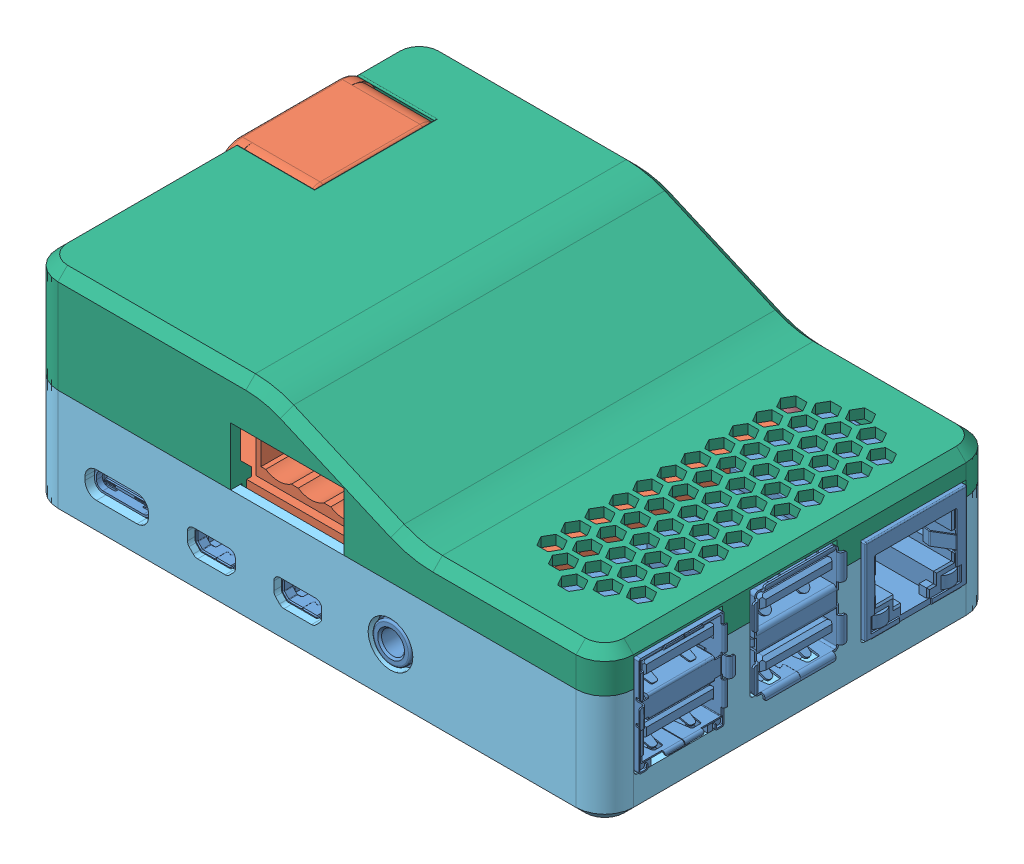
SolidWorks assembly AndroidAutoPi, configuration Default. Lengths in mm.
Overall size (91.49 34.28 61).
18 component instances, 7 part files, 35 mates.
Components (placement in the parent):
- Raspberry Pi 4 Model B-1: Raspberry Pi 4 Model B [Default] at (35.8475 44.9934 67.9064) size (88.99 19.9 58.4)
- PCB_AndroidAuto-1: PCB_AndroidAuto [Default] at (-6.6525 55.7834 95.9064) x (1 0 0) z (0 1 0) size (67.39 56 24.41)
- entretoiseM2.5x10_970100151-1: entretoiseM2.5x10_970100151 [Default] at (-3.1525 45.7834 92.4064) x (-0.708212 0 -0.705999) z (0.705999 0 -0.708212) size (6.35 10 5)
- entretoiseM2.5x10_970100151-2: entretoiseM2.5x10_970100151 [Default] at (54.8475 45.7834 92.4064) x (0.547024 0 -0.837117) z (0.837117 0 0.547024) size (6.35 10 5)
- entretoiseM2.5x10_970100151-3: entretoiseM2.5x10_970100151 [Default] at (-3.1525 45.7834 43.4064) size (6.35 10 5)
- entretoiseM2.5x10_970100151-4: entretoiseM2.5x10_970100151 [Default] at (54.8475 45.7834 43.4064) size (6.35 10 5)
- hexalobular socket pan head_iso-1: hexalobular socket pan head_iso [ISO 14583 - M2.5 x 3 x 2.1 - 4.8-N] at (54.8475 54.3834 43.4064) size (5 5.1 5)
- hexalobular socket pan head_iso-2: hexalobular socket pan head_iso [ISO 14583 - M2.5 x 3 x 2.1 - 4.8-N] at (54.8475 54.3834 92.4064) size (5 5.1 5)
- hexalobular socket pan head_iso-3: hexalobular socket pan head_iso [ISO 14583 - M2.5 x 3 x 2.1 - 4.8-N] at (-3.1525 54.3834 92.4064) size (5 5.1 5)
- hexalobular socket pan head_iso-4: hexalobular socket pan head_iso [ISO 14583 - M2.5 x 3 x 2.1 - 4.8-N] at (-3.1525 54.3834 43.4064) size (5 5.1 5)
- hexalobular socket pan head_iso-5: hexalobular socket pan head_iso [ISO 14583 - M2.5 x 6 x 5.1 - 4.8-N] at (54.8475 47.2034 43.4064) x (0.835617 0 0.549312) z (0.549312 0 -0.835617) size (5 8.1 5)
- hexalobular socket pan head_iso-6: hexalobular socket pan head_iso [ISO 14583 - M2.5 x 6 x 5.1 - 4.8-N] at (-3.1525 47.2034 43.4064) x (0.985596 0 0.169116) z (0.169116 0 -0.985596) size (5 8.1 5)
- hexalobular socket pan head_iso-7: hexalobular socket pan head_iso [ISO 14583 - M2.5 x 6 x 5.1 - 4.8-N] at (-3.1525 47.2034 92.4064) x (0.842129 0 0.539277) z (0.539277 0 -0.842129) size (5 8.1 5)
- hexalobular socket pan head_iso-8: hexalobular socket pan head_iso [ISO 14583 - M2.5 x 6 x 5.1 - 4.8-N] at (54.8475 47.2034 92.4064) x (0.76595 0 0.6429) z (0.6429 0 -0.76595) size (5 8.1 5)
- case_bottom-1: case_bottom [Défaut] at (35.8475 39.7034 67.9064) size (90 17.5 61)
- case_top-1: case_top [Défaut] at (35.8475 55.7034 67.9064) size (90 17.68 61)
- pxc_1757022_06_MSTB-2-5-3-ST-5-08_3D.stp-1: pxc_1757022_06_MSTB-2-5-3-ST-5-08_3D.stp [Défaut] at (23.6075 57.6575 104.8835) x (1 0 0) z (0 1 0) size (15.24 18.3 15)
  - MSTB_2.5_3-ST-5.08.stp-1: MSTB_2.5_3-ST-5.08.stp [Défaut] at (2.54 58.5267 -37.9127) x (0 -1 0) z (-1 0 0) size (18.3 15 15.24) (hidden)
Mates (geometry in assembly coordinates):
- Concentric3: concentric anti-aligned: cylinder of Raspberry Pi 4 Model B-1 through (-3.1525 45.7934 92.4064) axis (0 1 0) radius 1.35; cylinder of entretoiseM2.5x10-1 through (-3.1525 55.7834 92.4064) axis (0 -1 0) radius 1.25
- Coincident1: coincident anti-aligned: plane of Raspberry Pi 4 Model B-1 through (-3.1525 45.7834 92.4064) normal (0 1 0); plane of entretoiseM2.5x10-1 through (-3.1525 45.7834 92.4064) normal (0 -1 0)
- Concentric4: concentric anti-aligned: cylinder of Raspberry Pi 4 Model B-1 through (54.8475 45.7934 92.4064) axis (0 1 0) radius 1.35; cylinder of entretoiseM2.5x10-2 through (54.8475 55.7834 92.4064) axis (0 -1 0) radius 1.25
- Coincident2: coincident anti-aligned: plane of Raspberry Pi 4 Model B-1 through (54.8475 45.7834 92.4064) normal (0 1 0); plane of entretoiseM2.5x10-2 through (54.8475 45.7834 92.4064) normal (0 -1 0)
- Concentric5: concentric anti-aligned: cylinder of Raspberry Pi 4 Model B-1 through (-3.1525 45.7934 43.4064) axis (0 1 0) radius 1.35; cylinder of entretoiseM2.5x10-3 through (-3.1525 55.7834 43.4064) axis (0 -1 0) radius 1.25
- Coincident3: coincident anti-aligned: plane of Raspberry Pi 4 Model B-1 through (-3.1525 45.7834 43.4064) normal (0 1 0); plane of entretoiseM2.5x10-3 through (-3.1525 45.7834 43.4064) normal (0 -1 0)
- Concentric6: concentric anti-aligned: cylinder of Raspberry Pi 4 Model B-1 through (54.8475 45.7934 43.4064) axis (0 1 0) radius 1.35; cylinder of entretoiseM2.5x10-4 through (54.8475 55.7834 43.4064) axis (0 -1 0) radius 1.25
- Coincident4: coincident anti-aligned: plane of Raspberry Pi 4 Model B-1 through (54.8475 45.7834 43.4064) normal (0 1 0); plane of entretoiseM2.5x10-4 through (54.8475 45.7834 43.4064) normal (0 -1 0)
- Concentric11: concentric aligned: cylinder of Raspberry Pi 4 Model B-1 through (54.8475 45.7934 43.4064) axis (0 1 0) radius 1.35; cylinder of hexalobular socket pan head_iso-5 through (54.8475 47.2034 43.4064) axis (0 1 0) radius 2.5
- Concentric12: concentric aligned: cylinder of Raspberry Pi 4 Model B-1 through (-3.1525 45.7934 43.4064) axis (0 1 0) radius 1.35; cylinder of hexalobular socket pan head_iso-6 through (-3.1525 47.2034 43.4064) axis (0 1 0) radius 2.5
- Concentric13: concentric aligned: cylinder of Raspberry Pi 4 Model B-1 through (-3.1525 45.7934 92.4064) axis (0 1 0) radius 1.35; cylinder of hexalobular socket pan head_iso-7 through (-3.1525 47.2034 92.4064) axis (0 1 0) radius 2.5
- Concentric14: concentric aligned: cylinder of Raspberry Pi 4 Model B-1 through (54.8475 45.7934 92.4064) axis (0 1 0) radius 1.35; cylinder of hexalobular socket pan head_iso-8 through (54.8475 47.2034 92.4064) axis (0 1 0) radius 2.5
- Coaxiale1: concentric anti-aligned: cylinder of PCB_AndroidAuto-1 through (54.8475 54.9834 43.4064) axis (0 1 0) radius 1.35; cylinder of hexalobular socket pan head_iso-1 through (54.8475 54.3834 43.4064) axis (0 -1 0) radius 2.5
- Coïncidente1: coincident anti-aligned: plane of PCB_AndroidAuto-1 through (25.8475 57.3834 67.9064) normal (0 1 0); circle of hexalobular socket pan head_iso-1
- Coaxiale2: concentric anti-aligned: cylinder of PCB_AndroidAuto-1 through (54.8475 54.9834 92.4064) axis (0 1 0) radius 1.35; cylinder of hexalobular socket pan head_iso-2 through (54.8475 54.3834 92.4064) axis (0 -1 0) radius 1.55
- Coïncidente2: coincident anti-aligned: plane of PCB_AndroidAuto-1 through (25.8475 57.3834 67.9064) normal (0 1 0); circle of hexalobular socket pan head_iso-2
- Coaxiale3: concentric anti-aligned: cylinder of PCB_AndroidAuto-1 through (-3.1525 54.9834 92.4064) axis (0 1 0) radius 1.35; cylinder of hexalobular socket pan head_iso-3 through (-3.1525 54.3834 92.4064) axis (0 -1 0) radius 1.55
- Coïncidente3: coincident anti-aligned: plane of PCB_AndroidAuto-1 through (25.8475 57.3834 67.9064) normal (0 1 0); circle of hexalobular socket pan head_iso-3
- Coaxiale4: concentric anti-aligned: cylinder of PCB_AndroidAuto-1 through (-3.1525 54.9834 43.4064) axis (0 1 0) radius 1.35; cylinder of hexalobular socket pan head_iso-4 through (-3.1525 54.3834 43.4064) axis (0 -1 0) radius 1.55
- Coïncidente4: coincident anti-aligned: plane of PCB_AndroidAuto-1 through (25.8475 57.3834 67.9064) normal (0 1 0); circle of hexalobular socket pan head_iso-4
- Coaxiale5: concentric aligned: cylinder of entretoiseM2.5x10_970100151-3 through (-3.1525 55.7834 43.4064) axis (0 -1 0) radius 1.25; cylinder of hexalobular socket pan head_iso-4 through (-3.1525 54.3834 43.4064) axis (0 -1 0) radius 1.55
- Coaxiale6: concentric aligned: cylinder of entretoiseM2.5x10_970100151-2 through (54.8475 55.7834 92.4064) axis (0 -1 0) radius 1.25; cylinder of hexalobular socket pan head_iso-2 through (54.8475 54.3834 92.4064) axis (0 -1 0) radius 1.55
- Coïncidente5: coincident anti-aligned: plane of PCB_AndroidAuto-1 through (25.8475 55.7834 67.9064) normal (0 -1 0); plane of entretoiseM2.5x10_970100151-2 through (54.8475 55.7834 92.4064) normal (0 1 0)
- Largeur1: width aligned: plane of case_bottom-1 through (-9.1525 57.2034 98.4064) normal (0 0 1); plane of case_bottom-1 through (-9.1525 57.2034 37.4064) normal (0 0 -1); plane of Raspberry Pi 4 Model B-1 through (-6.6525 45.7934 95.9064) normal (0 0 1); plane of Raspberry Pi 4 Model B-1 through (-6.6525 45.7934 39.9064) normal (0 0 -1)
- Largeur2: width anti-aligned: plane of case_bottom-1 through (80.8475 57.2034 98.4064) normal (1 0 0); plane of case_bottom-1 through (-9.1525 57.2034 98.4064) normal (-1 0 0); plane of Raspberry Pi 4 Model B-1 through (-6.6525 45.7934 39.9064) normal (-1 0 0); plane of Raspberry Pi 4 Model B-1 through (78.3475 45.7934 39.9064) normal (1 0 0)
- Coïncidente6: coincident anti-aligned: plane of Raspberry Pi 4 Model B-1 through (54.8475 44.2034 43.4064) normal (0 -1 0); plane of case_bottom-1 through (54.8475 44.2034 43.4064) normal (0 1 0)
- Coïncidente7: coincident anti-aligned: circle of hexalobular socket pan head_iso-6; plane of case_bottom-1 through (-3.1525 41.2034 43.4064) normal (0 -1 0)
- Coïncidente8: coincident anti-aligned: circle of hexalobular socket pan head_iso-7; plane of case_bottom-1 through (-3.1525 41.2034 92.4064) normal (0 -1 0)
- Coïncidente9: coincident anti-aligned: circle of hexalobular socket pan head_iso-5; plane of case_bottom-1 through (54.8475 41.2034 43.4064) normal (0 -1 0)
- Coïncidente10: coincident anti-aligned: circle of hexalobular socket pan head_iso-8; plane of case_bottom-1 through (54.8475 41.2034 92.4064) normal (0 -1 0)
- Coaxiale7: concentric aligned: cylinder of case_bottom-1 through (-4.6525 57.2034 93.9064) axis (0 -1 0) radius 4.5; cylinder of case_top-1 through (-4.6525 73.3834 93.9064) axis (0 -1 0) radius 4.5
- Coaxiale8: concentric aligned: cylinder of case_bottom-1 through (76.3475 57.2034 41.9064) axis (0 -1 0) radius 4.5; cylinder of case_top-1 through (76.3475 73.3834 41.9064) axis (0 -1 0) radius 4.5
- Coïncidente12: coincident anti-aligned: plane of case_bottom-1 through (35.8475 57.2034 67.9064) normal (0 1 0); plane of case_top-1 through (-4.6525 57.2034 41.9064) normal (0 -1 0)
- Parallèle1: parallel anti-aligned: line of PCB_AndroidAuto-1 through (55.3475 57.3834 95.9064) axis (-1 0 0); line of pxc_1757022_06_MSTB-2-5-3-ST-5-08_3D.stp-1/MSTB_2.5_3-ST-5.08.stp-1 through (23.6075 57.6575 104.9835) axis (1 0 0)
- Largeur3: width aligned: plane of case_top-1 through (22.3575 66.2834 74.501) normal (1 0 0); plane of case_top-1 through (40.0975 66.2834 74.501) normal (-1 0 0); plane of pxc_1757022_06_MSTB-2-5-3-ST-5-08_3D.stp-1/MSTB_2.5_3-ST-5.08.stp-1 through (38.8475 19.7448 46.3568) normal (1 0 0); plane of pxc_1757022_06_MSTB-2-5-3-ST-5-08_3D.stp-1/MSTB_2.5_3-ST-5.08.stp-1 through (23.6075 19.7448 46.3568) normal (-1 0 0)
